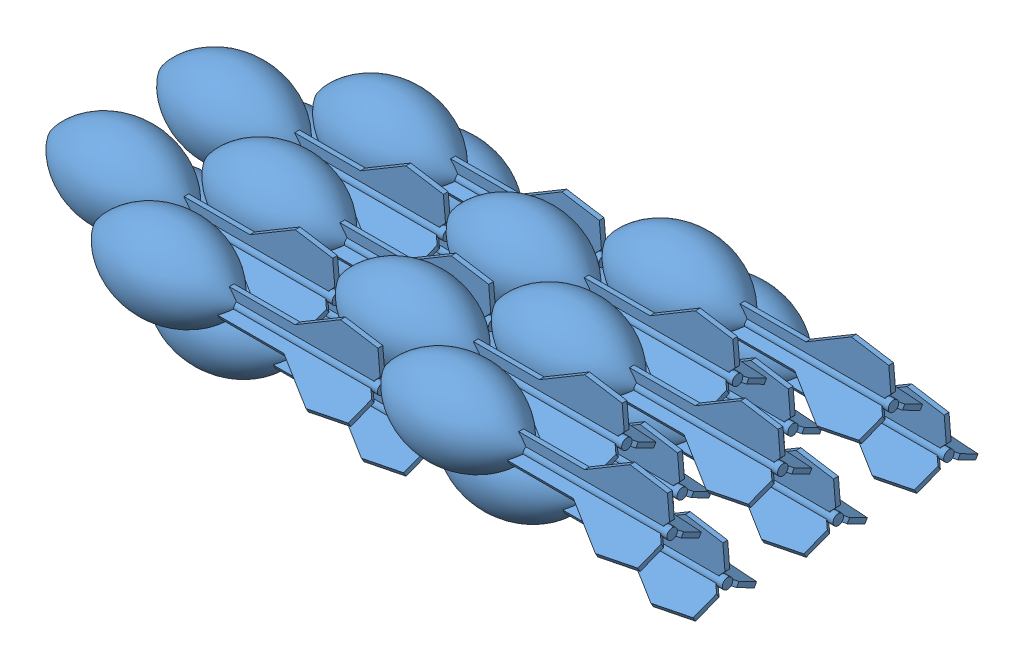
SolidWorks assembly Single Fuselage, configuration Default. Lengths in mm.
Overall size (718.36 184.15 323.77).
56 component instances, 1 part files, 11 mates.
Components (placement in the parent):
- 5 Football Layout-1: 5 Football Layout [Default] at (80.2791 -22.6018 -27.6297) size (520.31 88.9 323.62)
  - Habitat-1: Habitat [Default] at (63.8017 231.4109 497.8806) size (305.14 88.9 88.9)
  - Habitat-2: Habitat [Default] at (-42.7359 231.4109 439.3197) size (305.14 88.9 88.9)
  - Habitat-3: Habitat [Default] at (63.8017 231.4109 380.6103) size (305.14 88.9 88.9)
  - Habitat-4: Habitat [Default] at (-42.7359 231.4109 322.0494) size (305.14 88.9 88.9)
  - Habitat-5: Habitat [Default] at (63.8017 231.4109 263.3863) size (305.14 88.9 88.9)
  - Habitat-12: Habitat [Default] at (261.2704 251.8161 439.2455) x (1 -0.000016 0) z (0 0 1) size (305.14 88.9 88.9) (hidden)
  - Habitat-15: Habitat [Default] at (261.2704 251.8161 322.0214) x (1 -0.000016 0) z (0 0 1) size (305.14 88.9 88.9) (hidden)
  - Habitat-19: Habitat [Default] at (368.9446 251.8144 497.8806) x (1 -0.000016 0) z (0 0 1) size (305.14 88.9 88.9) (hidden)
  - Habitat-20: Habitat [Default] at (368.9446 251.8144 380.6103) x (1 -0.000016 0) z (0 0 1) size (305.14 88.9 88.9) (hidden)
  - Habitat-22: Habitat [Default] at (368.9446 251.8144 263.3863) x (1 -0.000016 0) z (0 0 1) size (305.14 88.9 88.9) (hidden)
  - Habitat-23: Habitat [Default] at (172.4361 231.4109 556.4416) size (305.14 88.9 88.9) (hidden)
  - Habitat-25: Habitat [Default] at (172.4361 231.4109 204.3824) size (305.14 88.9 88.9) (hidden)
  - Habitat-26: Habitat [Default] at (172.4361 231.4109 321.7202) size (305.14 88.9 88.9) (hidden)
- 5 Football Layout-2: 5 Football Layout [Default] at (386.9591 -2.2818 -27.6297) size (520.31 88.9 323.62)
  - Habitat-1: Habitat [Default] at (63.8017 231.4109 497.8806) size (305.14 88.9 88.9)
  - Habitat-2: Habitat [Default] at (-42.7359 231.4109 439.3197) size (305.14 88.9 88.9)
  - Habitat-3: Habitat [Default] at (63.8017 231.4109 380.6103) size (305.14 88.9 88.9)
  - Habitat-4: Habitat [Default] at (-42.7359 231.4109 322.0494) size (305.14 88.9 88.9)
  - Habitat-5: Habitat [Default] at (63.8017 231.4109 263.3863) size (305.14 88.9 88.9)
  - Habitat-12: Habitat [Default] at (261.2704 251.8161 439.2455) x (1 -0.000016 0) z (0 0 1) size (305.14 88.9 88.9) (hidden)
  - Habitat-15: Habitat [Default] at (261.2704 251.8161 322.0214) x (1 -0.000016 0) z (0 0 1) size (305.14 88.9 88.9) (hidden)
  - Habitat-19: Habitat [Default] at (368.9446 251.8144 497.8806) x (1 -0.000016 0) z (0 0 1) size (305.14 88.9 88.9) (hidden)
  - Habitat-20: Habitat [Default] at (368.9446 251.8144 380.6103) x (1 -0.000016 0) z (0 0 1) size (305.14 88.9 88.9) (hidden)
  - Habitat-22: Habitat [Default] at (368.9446 251.8144 263.3863) x (1 -0.000016 0) z (0 0 1) size (305.14 88.9 88.9) (hidden)
  - Habitat-23: Habitat [Default] at (172.4361 231.4109 556.4416) size (305.14 88.9 88.9) (hidden)
  - Habitat-25: Habitat [Default] at (172.4361 231.4109 204.3824) size (305.14 88.9 88.9) (hidden)
  - Habitat-26: Habitat [Default] at (172.4361 231.4109 321.7202) size (305.14 88.9 88.9) (hidden)
- 5 Football Layout-3: 5 Football Layout [Default] at (80.2791 -97.5318 -86.339) size (520.31 88.9 323.62)
  - Habitat-1: Habitat [Default] at (63.8017 231.4109 497.8806) size (305.14 88.9 88.9)
  - Habitat-2: Habitat [Default] at (-42.7359 231.4109 439.3197) size (305.14 88.9 88.9)
  - Habitat-3: Habitat [Default] at (63.8017 231.4109 380.6103) size (305.14 88.9 88.9)
  - Habitat-4: Habitat [Default] at (-42.7359 231.4109 322.0494) size (305.14 88.9 88.9)
  - Habitat-5: Habitat [Default] at (63.8017 231.4109 263.3863) size (305.14 88.9 88.9)
  - Habitat-12: Habitat [Default] at (261.2704 251.8161 439.2455) x (1 -0.000016 0) z (0 0 1) size (305.14 88.9 88.9) (hidden)
  - Habitat-15: Habitat [Default] at (261.2704 251.8161 322.0214) x (1 -0.000016 0) z (0 0 1) size (305.14 88.9 88.9) (hidden)
  - Habitat-19: Habitat [Default] at (368.9446 251.8144 497.8806) x (1 -0.000016 0) z (0 0 1) size (305.14 88.9 88.9) (hidden)
  - Habitat-20: Habitat [Default] at (368.9446 251.8144 380.6103) x (1 -0.000016 0) z (0 0 1) size (305.14 88.9 88.9) (hidden)
  - Habitat-22: Habitat [Default] at (368.9446 251.8144 263.3863) x (1 -0.000016 0) z (0 0 1) size (305.14 88.9 88.9) (hidden)
  - Habitat-23: Habitat [Default] at (172.4361 231.4109 556.4416) size (305.14 88.9 88.9) (hidden)
  - Habitat-25: Habitat [Default] at (172.4361 231.4109 204.3824) size (305.14 88.9 88.9) (hidden)
  - Habitat-26: Habitat [Default] at (172.4361 231.4109 321.7202) size (305.14 88.9 88.9) (hidden)
- 5 Football Layout-4: 5 Football Layout [Default] at (386.9591 -77.2118 -86.339) size (520.31 88.9 323.62)
  - Habitat-1: Habitat [Default] at (63.8017 231.4109 497.8806) size (305.14 88.9 88.9)
  - Habitat-2: Habitat [Default] at (-42.7359 231.4109 439.3197) size (305.14 88.9 88.9)
  - Habitat-3: Habitat [Default] at (63.8017 231.4109 380.6103) size (305.14 88.9 88.9)
  - Habitat-4: Habitat [Default] at (-42.7359 231.4109 322.0494) size (305.14 88.9 88.9)
  - Habitat-5: Habitat [Default] at (63.8017 231.4109 263.3863) size (305.14 88.9 88.9)
  - Habitat-12: Habitat [Default] at (261.2704 251.8161 439.2455) x (1 -0.000016 0) z (0 0 1) size (305.14 88.9 88.9) (hidden)
  - Habitat-15: Habitat [Default] at (261.2704 251.8161 322.0214) x (1 -0.000016 0) z (0 0 1) size (305.14 88.9 88.9) (hidden)
  - Habitat-19: Habitat [Default] at (368.9446 251.8144 497.8806) x (1 -0.000016 0) z (0 0 1) size (305.14 88.9 88.9) (hidden)
  - Habitat-20: Habitat [Default] at (368.9446 251.8144 380.6103) x (1 -0.000016 0) z (0 0 1) size (305.14 88.9 88.9) (hidden)
  - Habitat-22: Habitat [Default] at (368.9446 251.8144 263.3863) x (1 -0.000016 0) z (0 0 1) size (305.14 88.9 88.9) (hidden)
  - Habitat-23: Habitat [Default] at (172.4361 231.4109 556.4416) size (305.14 88.9 88.9) (hidden)
  - Habitat-25: Habitat [Default] at (172.4361 231.4109 204.3824) size (305.14 88.9 88.9) (hidden)
  - Habitat-26: Habitat [Default] at (172.4361 231.4109 321.7202) size (305.14 88.9 88.9) (hidden)
Mates (geometry in assembly coordinates):
- Parallel1: parallel aligned: plane of 5 Football Layout-1 through (80.2791 -22.6018 -27.6297) normal (0 1 0); plane of 5 Football Layout-2 through (386.9591 -2.2818 -27.6297) normal (0 1 0)
- Parallel2: parallel aligned: plane of 5 Football Layout-1/Habitat-2 through (37.5431 208.8091 411.69) normal (1 0 0); plane of 5 Football Layout-2 through (386.9591 -2.2818 -27.6297) normal (1 0 0)
- Coincident5: coincident aligned: plane of 5 Football Layout-1/Habitat-1 through (144.0808 208.8091 472.7909) normal (0 0 1); plane of 5 Football Layout-2/Habitat-1 through (450.7608 229.1291 472.7909) normal (0 0 1)
- Coincident6: coincident aligned: plane of 5 Football Layout-1 through (297.1191 -22.6018 -27.6297) normal (1 0 0); plane of 5 Football Layout-2 through (297.1191 -2.2818 -27.6297) normal (1 0 0)
- Coincident7: coincident aligned: plane of 5 Football Layout-2/Habitat-1 through (450.7608 229.1291 470.2509) normal (0 1 0)
- Coincident11: coincident aligned: plane of 5 Football Layout-1 through (-116.2409 -22.6018 -27.6297) normal (1 0 0); plane of 5 Football Layout-3 through (-116.2409 -97.5318 -86.339) normal (1 0 0)
- Distance3: distance = 74.93 mm aligned: plane of 5 Football Layout-1/Habitat-1 through (144.0808 208.8091 470.2509) normal (0 1 0); plane of 5 Football Layout-3/Habitat-1 through (144.0808 133.8791 411.5416) normal (0 1 0)
- Coincident12: coincident aligned: plane of 5 Football Layout-1/Habitat-3 through (144.0808 208.8091 355.5206) normal (0 0 1); plane of 5 Football Layout-3/Habitat-2 through (37.5431 133.8791 355.5206) normal (0 0 1)
- Coincident13: coincident aligned: plane of 5 Football Layout-2 through (190.4391 -2.2818 -27.6297) normal (1 0 0); plane of 5 Football Layout-4 through (190.4391 -77.2118 -86.339) normal (1 0 0)
- Distance4: distance = 74.93 mm aligned: plane of 5 Football Layout-2/Habitat-1 through (450.7608 229.1291 470.2509) normal (0 1 0); plane of 5 Football Layout-4/Habitat-1 through (450.7608 154.1991 411.5416) normal (0 1 0)
- Coincident14: coincident aligned: plane of 5 Football Layout-2/Habitat-3 through (450.7608 229.1291 355.5206) normal (0 0 1); plane of 5 Football Layout-4/Habitat-2 through (344.2231 154.1991 355.5206) normal (0 0 1)
